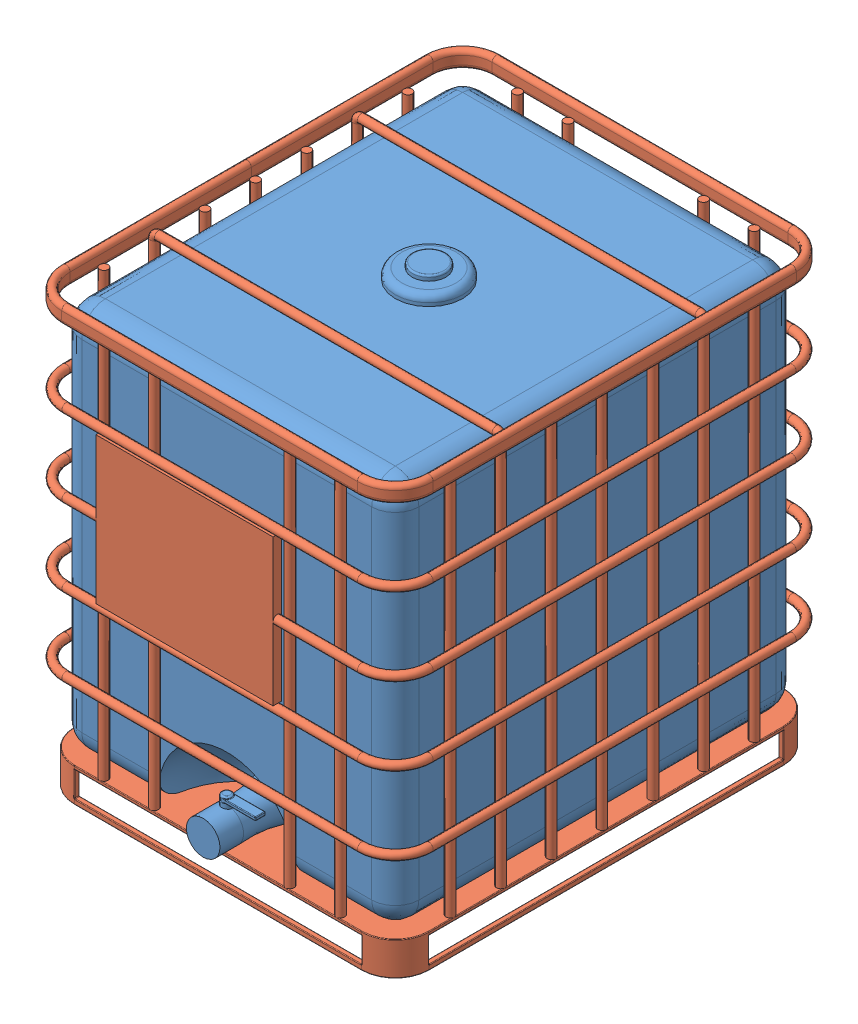
SolidWorks assembly Assem1, configuration Default. Lengths in mm.
Overall size (1102.02 1295 1321.01).
2 component instances, 2 part files, 3 mates.
Components (placement in the parent):
- Part3-1: Part3 [Default] at (-181.901 221.4756 1533.389) size (1000 1201.2 1270)
- Part4-1: Part4 [Default] at (315.9185 211.4756 932.0806) size (1102.02 1287.5 1302.03)
Mates (geometry in assembly coordinates):
- Coincident1: coincident anti-aligned: plane of Part3-1 through (-181.901 221.4756 1533.389) normal (0 -1 0); plane of Part4-1 through (-107.901 221.4756 1459.389) normal (0 1 0)
- Distance1: distance = 26 mm aligned: plane of Part3-1 through (-181.901 1371.4756 1533.389) normal (0 0 1); plane of Part4-1 through (744.099 221.4756 1559.389) normal (0 0 1)
- Distance2: distance = 26 mm aligned: plane of Part3-1 through (818.099 1371.4756 1533.389) normal (1 0 0); plane of Part4-1 through (844.099 221.4756 407.389) normal (1 0 0)
